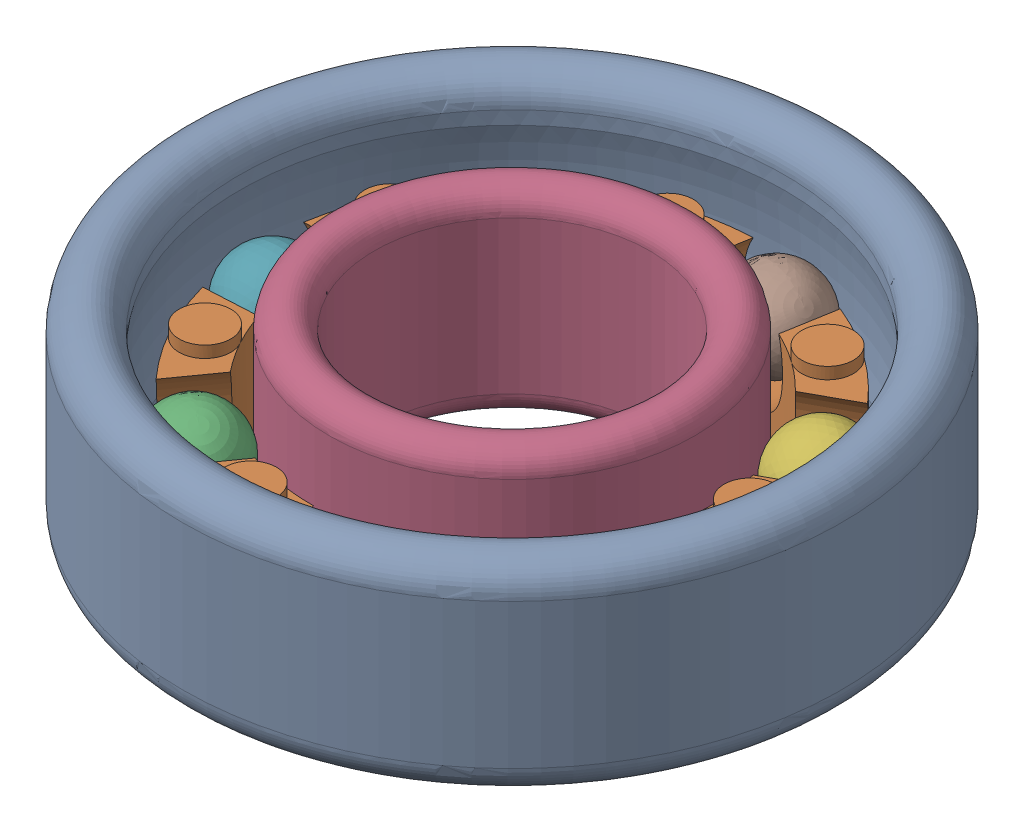
SolidWorks assembly Bearing, configuration Default. Lengths in mm.
Overall size (13.45 3.96 13.45).
10 component instances, 4 part files, 19 mates.
Components (placement in the parent):
- DR41BR2-1: DR41BR2 [Default] at origin size (12.95 3.96 12.95)
- DR41BR3-1: DR41BR3 [Default] x (-0.481059 0 -0.876688) z (0.876688 0 -0.481059) size (9.91 2.67 9.91)
- DR41BR4-1: DR41BR4 [Default] at (-2.6053 1.8415 3.6483) x (-0.726998 0.449387 -0.519159) z (-0.581145 0 0.8138) size (1.78 1.78 1.78)
- DR41BR1-1: DR41BR1 [Default] x (-0.734194 0 0.67894) z (-0.67894 0 -0.734194) size (7.19 3.89 7.19)
- DR41BR4-2: DR41BR4 [Default] at (4.1366 1.8415 1.7282) x (-0.248 0.765579 0.593621) z (0.922713 0 0.385487) size (1.78 1.78 1.78)
- DR41BR4-3: DR41BR4 [Default] at (3.9303 1.8415 -2.1566) x (-0.173482 -0.932711 -0.316157) z (0.876688 0 -0.481059) size (1.78 1.78 1.78)
- DR41BR4-4: DR41BR4 [Default] at (-4.4768 1.8415 0.2378) x (-0.022107 -0.908994 -0.416222) z (-0.998592 0 0.053038) size (1.78 1.78 1.78)
- DR41BR4-5: DR41BR4 [Default] at (0.7644 1.8415 -4.4175) x (-0.622684 0.77502 -0.107745) z (0.170499 0 -0.985358) size (1.78 1.78 1.78)
- DR41BR4-6: DR41BR4 [Default] at (1.228 1.8415 4.3116) x (0.949305 0.160376 -0.270371) z (0.273916 0 0.961754) size (1.78 1.78 1.78)
- DR41BR4-7: DR41BR4 [Default] at (-2.9771 1.8415 -3.3518) x (0.58566 -0.621617 -0.520187) z (-0.664079 0 -0.747662) size (1.78 1.78 1.78)
Mates (geometry in assembly coordinates):
- Coincident1: coincident: line of assembly; axis of DR41BR2-1 through (9.4142 0 -1.1569) axis (0 0 1); axis of DR41BR1-1 through (0 3.4417 0) axis (0 -1 0)
- Concentric1: concentric aligned: cylinder of Outer Bearing-1 through (0 3.9624 0) axis (0 -1 0) radius 6.477; cylinder of Inner Bearing-1 through (0 3.8862 0) axis (0 -1 0) radius 3.5941
- Concentric3: concentric aligned: cylinder of Outer Bearing-1 through (0 3.9624 0) axis (0 -1 0) radius 6.477; cylinder of Bearing Pocket-1 through (0 2.4384 0) axis (0 -1 0) radius 4.953
- Concentric5: concentric anti-aligned: cylinder of Bearing Pocket-1 through (1.6249 1.8415 5.7053) axis (-0.273916 0 -0.961754) radius 1.2065; circle of Ball Bearing-6
- Concentric6: concentric anti-aligned: cylinder of Bearing Pocket-1 through (6.4239 1.8415 2.6837) axis (-0.922713 0 -0.385487) radius 1.2065; circle of Ball Bearing-2
- Concentric7: concentric anti-aligned: cylinder of Bearing Pocket-1 through (4.3431 1.8415 -2.3832) axis (-0.876688 0 0.481059) radius 1.2065; circle of Ball Bearing-3
- Concentric8: concentric anti-aligned: cylinder of Bearing Pocket-1 through (1.187 1.8415 -6.86) axis (-0.170499 0 0.985358) radius 1.2065; circle of Ball Bearing-5
- Concentric9: concentric anti-aligned: cylinder of Bearing Pocket-1 through (-3.9394 1.8415 -4.4353) axis (0.664079 0 0.747662) radius 1.2065; circle of Ball Bearing-7
- Concentric10: concentric anti-aligned: cylinder of Bearing Pocket-1 through (-6.6036 1.8415 0.3507) axis (0.998592 0 -0.053038) radius 1.2065; circle of Ball Bearing-4
- Tangent12: tangent aligned: torus of Outer Bearing-1; plane of Bearing Pocket-1 through (0 0 0) normal (0 -1 0)
- Tangent21: tangent aligned: plane of Bearing Pocket-1 through (0 0 0) normal (0 -1 0); edge_curve of Inner Bearing-1
- Concentric11: concentric anti-aligned: cylinder of Bearing Pocket-1 through (-3.843 1.8415 5.3815) axis (0.581145 0 -0.8138) radius 1.2065; circle of Ball Bearing-1
- Tangent13: tangent anti-aligned: sphere of Inner Bearing-1; unknown of Ball Bearing-3
- Tangent14: tangent anti-aligned: cylinder of Inner Bearing-1 through (0 3.8862 0) axis (0 -1 0) radius 3.5941; unknown of Ball Bearing-5
- Tangent15: tangent anti-aligned: cylinder of Inner Bearing-1 through (0 3.8862 0) axis (0 -1 0) radius 3.5941; unknown of Ball Bearing-7
- Tangent17: tangent anti-aligned: cylinder of Inner Bearing-1 through (0 3.8862 0) axis (0 -1 0) radius 3.5941; unknown of Ball Bearing-2
- Tangent18: tangent anti-aligned: cylinder of Inner Bearing-1 through (0 3.8862 0) axis (0 -1 0) radius 3.5941; unknown of Ball Bearing-1
- Tangent19: tangent anti-aligned: cylinder of Inner Bearing-1 through (0 3.8862 0) axis (0 -1 0) radius 3.5941; unknown of Ball Bearing-6
- Tangent20: tangent anti-aligned: cylinder of Inner Bearing-1 through (0 3.8862 0) axis (0 -1 0) radius 3.5941; unknown of Ball Bearing-4
